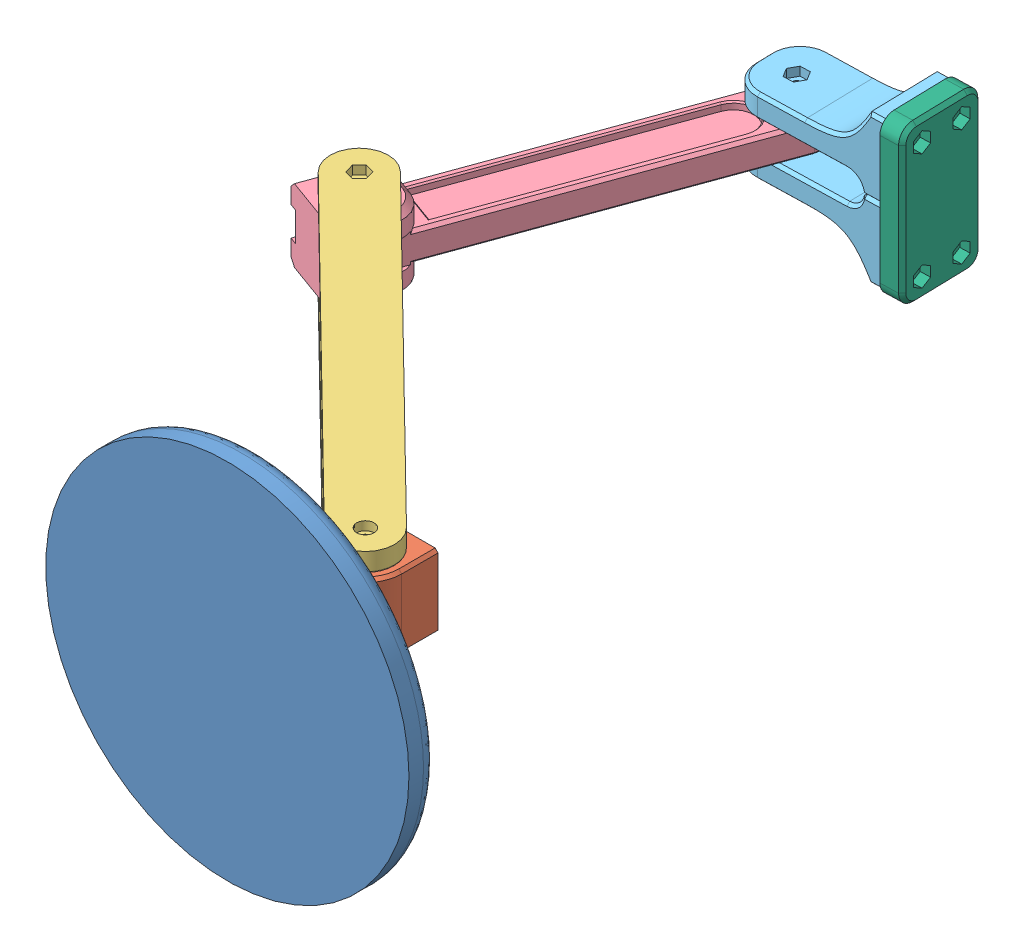
SolidWorks assembly Pi_Cam_Assembl_V1, configuration Default. Lengths in mm.
Overall size (185.62 125 278.14).
8 component instances, 6 part files, 19 mates.
Components (placement in the parent):
- Base-1: Base [Default] at (33.0577 51.573 96.9277) size (125 125 35)
- Arm_To_Base_Connector-1: Arm_To_Base_Connector [Default] at (33.0577 64.073 49.4277) x (1 0 0) z (0 -1 0) size (25 45 25)
- Arm_Main-1: Arm_Main [Default] at (-20.4946 32.573 -3.0809) x (-0.71403 0 -0.700115) z (0 1 0) size (170 20 6.5)
- Arm_Main-2: Arm_Main [Default] at (-20.4946 70.573 -3.0809) x (0.71403 0 0.700115) z (0 -1 0) size (170 20 6.5)
- Arm_2-1: Arm_2 [Default] at (-78.317 51.573 -43.8415) x (0 -1 0) z (0.939843 0 0.341607) size (25 140 25)
- Mount_For_Camera-1: Mount_For_Camera [Left_Side] at (7.2866 51.573 -167.0216) x (0 -1 0) z (-0.025409 0 -0.999677) size (25.62 52.5 25.25)
- Mount_For_Camera-2: Mount_For_Camera [Right_Side] at (7.2866 51.573 -167.0216) x (0 1 0) z (0.025409 0 0.999677) size (28.12 52.5 25.25)
- Camera_Mount_Joiner-1: Camera_Mount_Joiner [Default] at (7.2866 51.573 -167.0216) x (0 -1 0) z (0.999677 0 -0.025409) size (54 28 7.5)
Mates (geometry in assembly coordinates):
- Concentric1: concentric anti-aligned: cylinder of Base-1 through (33.0577 51.573 61.9277) axis (0 0 1) radius 5; cylinder of Arm_To_Base_Connector-1 through (33.0577 51.573 81.9277) axis (0 0 -1) radius 4.95
- Concentric2: concentric aligned: cylinder of Base-1 through (33.0577 61.573 71.9277) axis (0 1 0) radius 1.55; cylinder of Arm_To_Base_Connector-1 through (33.0577 11.523 71.9277) axis (0 1 0) radius 1.55
- Coincident1: coincident: circle of Arm_To_Base_Connector-1; circle of Arm_Main-1
- Coincident2: coincident: circle of Arm_To_Base_Connector-1; circle of Arm_Main-2
- Coincident4: coincident aligned: plane of Arm_Main-1 through (-27.4958 36.573 4.0594) normal (-0.700115 0 0.71403); plane of Arm_Main-2 through (-27.4958 66.573 4.0594) normal (-0.700115 0 0.71403)
- Concentric5: concentric anti-aligned: circle of Arm_2-1; circle of Mount_For_Camera-1
- Coincident6: coincident anti-aligned: plane of Arm_2-1 through (-30.492 56.573 -175.4195) normal (0 1 0); plane of Mount_For_Camera-1 through (-45.1965 56.573 -165.6876) normal (0 -1 0)
- Concentric6: concentric aligned: circle of Arm_2-1; circle of Mount_For_Camera-2
- Coincident7: coincident anti-aligned: plane of Arm_2-1 through (-30.492 46.573 -175.4195) normal (0 -1 0); plane of Mount_For_Camera-2 through (-45.1965 46.573 -165.6876) normal (0 1 0)
- Coincident8: coincident aligned: plane of Mount_For_Camera-1 through (7.2866 51.573 -167.0216) normal (0.999677 0 -0.025409); plane of Mount_For_Camera-2 through (7.2866 51.573 -167.0216) normal (0.999677 0 -0.025409)
- Concentric7: concentric anti-aligned: circle of Arm_Main-2; circle of Arm_2-1
- Concentric8: concentric aligned: circle of Arm_To_Base_Connector-1; circle of Arm_Main-1
- Concentric9: concentric aligned: circle of Arm_To_Base_Connector-1; circle of Arm_Main-2
- Coincident9: coincident anti-aligned: plane of Arm_Main-1 through (33.0577 39.073 49.4277) normal (0 1 0); plane of Arm_2-1 through (-69.7768 39.073 -67.3376) normal (0 -1 0)
- Coincident10: coincident anti-aligned: plane of Arm_To_Base_Connector-1 through (33.0577 39.073 49.4277) normal (0 -1 0); plane of Arm_Main-1 through (33.0577 39.073 49.4277) normal (0 1 0)
- Concentric10: concentric anti-aligned: circle of Mount_For_Camera-1; circle of Camera_Mount_Joiner-1
- Concentric11: concentric anti-aligned: circle of Mount_For_Camera-2; circle of Camera_Mount_Joiner-1
- Coincident14: coincident anti-aligned: plane of Mount_For_Camera-1 through (7.2866 51.573 -167.0216) normal (0.999677 0 -0.025409); plane of Camera_Mount_Joiner-1 through (7.2866 51.573 -167.0216) normal (-0.999677 0 0.025409)
- Coincident15: coincident anti-aligned: plane of Arm_To_Base_Connector-1 through (33.0577 64.073 49.4277) normal (0 1 0); plane of Arm_Main-2 through (-74.0469 64.073 -55.5895) normal (0 -1 0)
